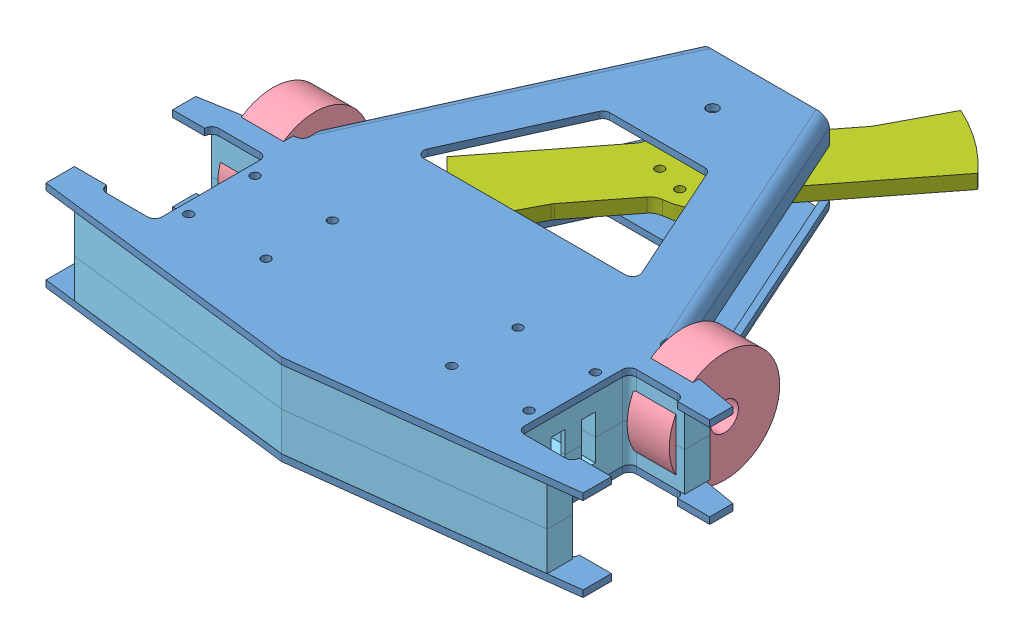
SolidWorks assembly El granjero, configuration Predeterminado. Lengths in mm.
Overall size (243.05 50 277.41).
11 component instances, 7 part files, 16 mates.
Components (placement in the parent):
- chasis 3lb-1: chasis 3lb [Tapa arriba] at (-24.4578 25.9948 231.15) size (243.05 12.26 219.46)
- chasis 3lb-3: chasis 3lb [Tapa abajo] at (-24.4578 -9.0052 231.15) x (-1 0 0) z (0 0 1) size (243.05 7.26 219.46)
- Motor arma KD 36-12L-1: Motor arma KD 36-12L [Predeterminado] at (-24.4578 -9.0052 198.15) size (36 29 36)
- Caja planetaria 3lb servocity-1: Caja planetaria 3lb servocity [Predeterminado] at (-83.1816 8.4948 181.9788) x (0 1 0) z (0 0 1) size (18 54.7 18)
- Caja planetaria 3lb servocity-2: Caja planetaria 3lb servocity [Predeterminado] at (32.5358 8.4948 183.7703) x (0 -0.987687 -0.156443) z (0 -0.156443 0.987687) size (18 54.7 18)
- Rueda 3lb-1: Rueda 3lb [Predeterminado] at (78.5922 8.4948 183.7703) x (0 1 0) z (0 0 1) size (50 19.05 50)
- Rueda 3lb-2: Rueda 3lb [Predeterminado] at (-108.4578 8.4948 181.9788) x (0 1 0) z (0 0 1) size (50 19.05 50)
- NUEVO SOPORTE DE MOTOR-1: NUEVO SOPORTE DE MOTOR [Predeterminado] at (-24.4578 -9.0052 223.925) size (214 17.5 91.9)
- NUEVO SOPORTE DE MOTOR-2: NUEVO SOPORTE DE MOTOR [Predeterminado] at (-24.4578 25.9948 223.925) x (-1 0 0) z (0 0 1) size (214 17.5 91.9)
- poleamotorarma-1: poleamotorarma [Predeterminado] at (-24.4578 12.4948 198.15) x (1 0 0) z (0 -1 0) size (48 48 15)
- Arma3lbv2-1: Arma3lbv2 [Predeterminado] at (-24.4578 0.3889 86.15) x (0.614702 0 -0.78876) z (0.78876 0 0.614702) size (170 6.35 50)
Mates (geometry in assembly coordinates):
- Distancia3: distance = 35 mm anti-aligned: plane of chasis 3lb-3 through (-24.4578 -9.0052 231.15) normal (0 1 0); plane of chasis 3lb-1 through (-24.4578 25.9948 231.15) normal (0 -1 0)
- Coincidente9: coincident aligned: plane of chasis 3lb-1 through (57.5422 28.9948 231.15) normal (1 0 0); plane of chasis 3lb-3 through (57.5422 -12.0052 231.15) normal (1 0 0)
- Coincidente10: coincident aligned: plane of chasis 3lb-1 through (-45.9652 16.7437 111.15) normal (0 0 1); plane of chasis 3lb-3 through (-2.9503 -4.7541 111.15) normal (0 0 1)
- Coincidente11: coincident anti-aligned: plane of chasis 3lb-3 through (-24.4578 -9.0052 231.15) normal (0 1 0); plane of Motor arma KD 36-12L-1 through (-24.4578 -9.0052 198.15) normal (0 -1 0)
- Concéntrica2: concentric aligned: cylinder of chasis 3lb-3 through (-24.4578 -4.7541 198.15) axis (0 -1 0) radius 4.7625; cylinder of Motor arma KD 36-12L-1 through (-24.4578 19.9948 198.15) axis (0 -1 0) radius 18
- Concéntrica9: concentric aligned: cylinder of Caja planetaria 3lb servocity-1 through (-119.8816 8.4948 181.9788) axis (1 0 0) radius 2; cylinder of Rueda 3lb-2 through (-127.5078 8.4948 181.9788) axis (1 0 0) radius 25
- Concéntrica10: concentric anti-aligned: cylinder of Caja planetaria 3lb servocity-2 through (69.2358 8.4948 183.7703) axis (-1 0 0) radius 2; cylinder of Rueda 3lb-1 through (59.5422 8.4948 183.7703) axis (1 0 0) radius 25
- Coincidente18: coincident anti-aligned: plane of chasis 3lb-3 through (-24.4578 -9.0052 231.15) normal (0 1 0); plane of NUEVO SOPORTE DE MOTOR-1 through (-24.4578 -9.0052 223.925) normal (0 -1 0)
- Concéntrica11: concentric aligned: cylinder of chasis 3lb-3 through (-101.4578 -4.7541 246.15) axis (0 -1 0) radius 2; cylinder of NUEVO SOPORTE DE MOTOR-1 through (-101.4578 8.4948 246.15) axis (0 -1 0) radius 2
- Concéntrica12: concentric aligned: cylinder of chasis 3lb-3 through (52.5422 -4.7541 246.15) axis (0 -1 0) radius 2; cylinder of NUEVO SOPORTE DE MOTOR-1 through (52.5422 8.4948 246.15) axis (0 -1 0) radius 2
- Coincidente19: coincident anti-aligned: plane of NUEVO SOPORTE DE MOTOR-1 through (-24.4578 8.4948 223.925) normal (0 1 0); plane of NUEVO SOPORTE DE MOTOR-2 through (-24.4578 8.4948 223.925) normal (0 -1 0)
- Concéntrica13: concentric anti-aligned: cylinder of NUEVO SOPORTE DE MOTOR-1 through (-101.4578 8.4948 246.15) axis (0 -1 0) radius 2; cylinder of NUEVO SOPORTE DE MOTOR-2 through (-101.4578 8.4948 246.15) axis (0 1 0) radius 2
- Concéntrica14: concentric anti-aligned: cylinder of NUEVO SOPORTE DE MOTOR-1 through (17.5422 8.4948 246.15) axis (0 -1 0) radius 2; cylinder of NUEVO SOPORTE DE MOTOR-2 through (17.5422 8.4948 246.15) axis (0 1 0) radius 2
- Concéntrica16: concentric aligned: cylinder of Motor arma KD 36-12L-1 through (-24.4578 19.9948 198.15) axis (0 -1 0) radius 18; cylinder of poleamotorarma-1 through (-24.4578 4.9948 198.15) axis (0 -1 0) radius 18
- Coincidente20: coincident aligned: plane of Motor arma KD 36-12L-1 through (-24.4578 19.9948 198.15) normal (0 1 0); plane of poleamotorarma-1 through (-6.4578 19.9948 198.15) normal (0 1 0)
- Concéntrica17: concentric aligned: cylinder of chasis 3lb-3 through (-24.4578 -12.0052 86.15) axis (0 -1 0) radius 2.5; cylinder of Arma3lbv2-1 through (-24.4578 6.7389 86.15) axis (0 -1 0) radius 5
